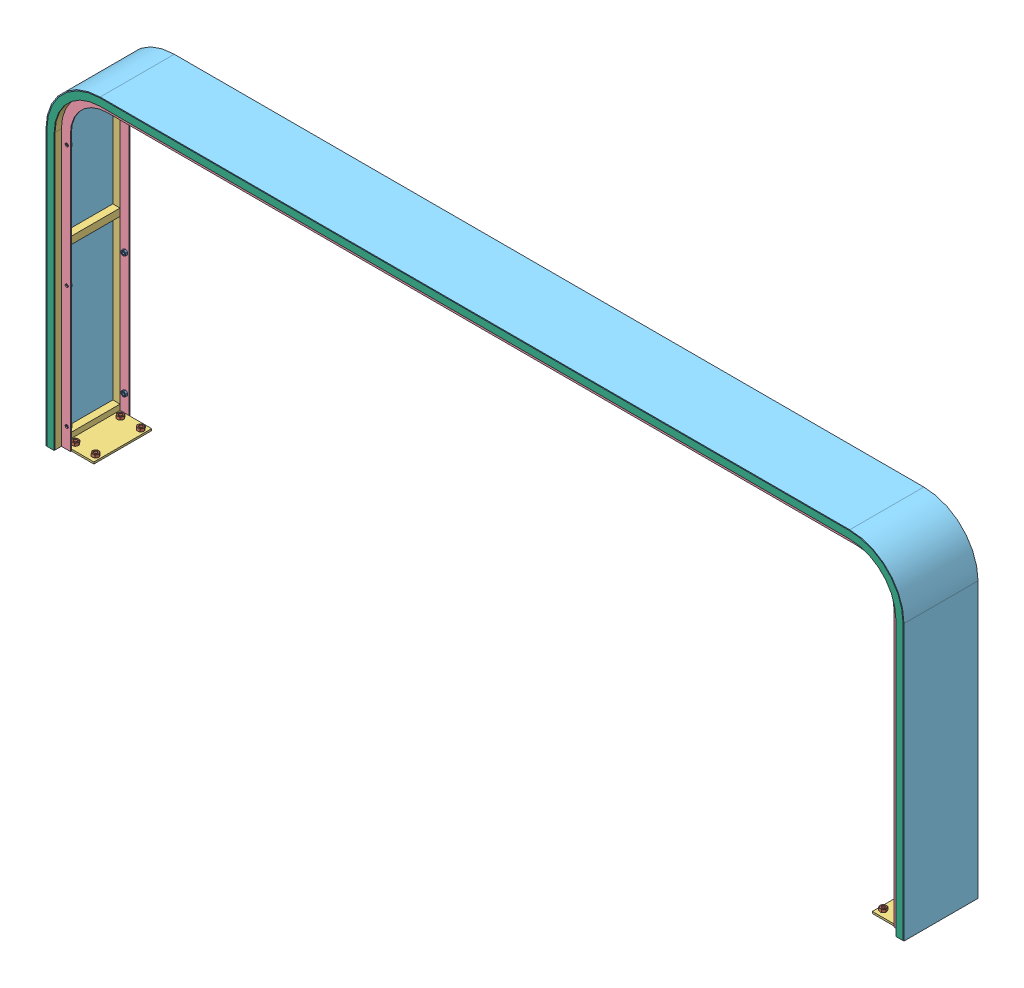
SolidWorks assembly wallFrame1, configuration Default. Lengths in mm.
Overall size (1900 729 164).
36 component instances, 6 part files, 33 mates.
Components (placement in the parent):
- GB_FASTENER_NUT_SNAB1 M6-C-12: GB_FASTENER_NUT_SNAB1 M6-C [GB_FASTENER_NUT_SNAB1 M6-C] at (-920 15 64.0012) x (0.923728 0.383049 0) z (0 0 1) size (11.55 10 5.2)
- GB_FASTENER_NUT_SNAB1 M8-C-5: GB_FASTENER_NUT_SNAB1 M8-C [GB_FASTENER_NUT_SNAB1 M8-C] at (917 -25.0014 -50) x (-0.991729 0 -0.128348) z (0 -1 0) size (15.01 13 6.8)
- table-wallFrame-bone-1: table-wallFrame-bone [Default] at origin size (1896 727 160)
- table-wallFrame-Ufix-1: table-wallFrame-Ufix [Default] at origin size (1864 711 2)
- table-wallFrame-sideshell-1: table-wallFrame-sideshell [Default] at origin size (1900 729 164)
- table-wallFrame-Ushell-1: table-wallFrame-Ushell [Default] at (0 0 -162) size (1896 727 2)
- GB_FASTENER_NUT_SNAB1 M6-C-1: GB_FASTENER_NUT_SNAB1 M6-C [GB_FASTENER_NUT_SNAB1 M6-C] at (-920 15 -58.8) x (0.923728 0.383049 0) z (0 0 1) size (11.55 10 5.2)
- table-wallFrame-Ufix-2: table-wallFrame-Ufix [Default] at (0 0 130) size (1864 711 2)
- table-wallFrame-Ushell-2: table-wallFrame-Ushell [Default] at origin size (1896 727 2)
- GB_FASTENER_NUT_SNAB1 M6-C-23: GB_FASTENER_NUT_SNAB1 M6-C [GB_FASTENER_NUT_SNAB1 M6-C] at (-920 285 -58.8) x (0.923728 0.383049 0) z (0 0 1) size (11.55 10 5.2)
- GB_FASTENER_NUT_SNAB1 M6-C-24: GB_FASTENER_NUT_SNAB1 M6-C [GB_FASTENER_NUT_SNAB1 M6-C] at (-920 555 -58.8) x (0.923728 0.383049 0) z (0 0 1) size (11.55 10 5.2)
- GB_FASTENER_NUT_SNAB1 M6-C-25: GB_FASTENER_NUT_SNAB1 M6-C [GB_FASTENER_NUT_SNAB1 M6-C] at (-800 670 -58.8) x (0.923728 0.383049 0) z (0 0 1) size (11.55 10 5.2)
- GB_FASTENER_NUT_SNAB1 M6-C-26: GB_FASTENER_NUT_SNAB1 M6-C [GB_FASTENER_NUT_SNAB1 M6-C] at (-400 670 -58.8) x (0.923728 0.383049 0) z (0 0 1) size (11.55 10 5.2)
- GB_FASTENER_NUT_SNAB1 M6-C-27: GB_FASTENER_NUT_SNAB1 M6-C [GB_FASTENER_NUT_SNAB1 M6-C] at (0 670 -58.8) x (0.923728 0.383049 0) z (0 0 1) size (11.55 10 5.2)
- GB_FASTENER_NUT_SNAB1 M6-C-28: GB_FASTENER_NUT_SNAB1 M6-C [GB_FASTENER_NUT_SNAB1 M6-C] at (400 670 -58.8) x (0.923728 0.383049 0) z (0 0 1) size (11.55 10 5.2)
- GB_FASTENER_NUT_SNAB1 M6-C-29: GB_FASTENER_NUT_SNAB1 M6-C [GB_FASTENER_NUT_SNAB1 M6-C] at (800 670 -58.8) x (0.923728 0.383049 0) z (0 0 1) size (11.55 10 5.2)
- GB_FASTENER_NUT_SNAB1 M6-C-30: GB_FASTENER_NUT_SNAB1 M6-C [GB_FASTENER_NUT_SNAB1 M6-C] at (920 555 -58.8) x (0.923728 0.383049 0) z (0 0 1) size (11.55 10 5.2)
- GB_FASTENER_NUT_SNAB1 M6-C-31: GB_FASTENER_NUT_SNAB1 M6-C [GB_FASTENER_NUT_SNAB1 M6-C] at (920 285 -58.8) x (0.923728 0.383049 0) z (0 0 1) size (11.55 10 5.2)
- GB_FASTENER_NUT_SNAB1 M6-C-32: GB_FASTENER_NUT_SNAB1 M6-C [GB_FASTENER_NUT_SNAB1 M6-C] at (920 15 -58.8) x (0.923728 0.383049 0) z (0 0 1) size (11.55 10 5.2)
- GB_FASTENER_NUT_SNAB1 M8-C-4: GB_FASTENER_NUT_SNAB1 M8-C [GB_FASTENER_NUT_SNAB1 M8-C] at (-917 -18.2 -50) x (0.991729 0 -0.128348) z (0 1 0) size (15.01 13 6.8)
- GB_FASTENER_NUT_SNAB1 M6-C-33: GB_FASTENER_NUT_SNAB1 M6-C [GB_FASTENER_NUT_SNAB1 M6-C] at (-920 285 64.0012) x (0.923728 0.383049 0) z (0 0 1) size (11.55 10 5.2)
- GB_FASTENER_NUT_SNAB1 M6-C-34: GB_FASTENER_NUT_SNAB1 M6-C [GB_FASTENER_NUT_SNAB1 M6-C] at (-920 555 64.0012) x (0.923728 0.383049 0) z (0 0 1) size (11.55 10 5.2)
- GB_FASTENER_NUT_SNAB1 M6-C-35: GB_FASTENER_NUT_SNAB1 M6-C [GB_FASTENER_NUT_SNAB1 M6-C] at (-800 670 64.0012) x (0.923728 0.383049 0) z (0 0 1) size (11.55 10 5.2)
- GB_FASTENER_NUT_SNAB1 M6-C-36: GB_FASTENER_NUT_SNAB1 M6-C [GB_FASTENER_NUT_SNAB1 M6-C] at (-400 670 64.0012) x (0.923728 0.383049 0) z (0 0 1) size (11.55 10 5.2)
- GB_FASTENER_NUT_SNAB1 M6-C-37: GB_FASTENER_NUT_SNAB1 M6-C [GB_FASTENER_NUT_SNAB1 M6-C] at (0 670 64.0012) x (0.923728 0.383049 0) z (0 0 1) size (11.55 10 5.2)
- GB_FASTENER_NUT_SNAB1 M6-C-38: GB_FASTENER_NUT_SNAB1 M6-C [GB_FASTENER_NUT_SNAB1 M6-C] at (400 670 64.0012) x (0.923728 0.383049 0) z (0 0 1) size (11.55 10 5.2)
- GB_FASTENER_NUT_SNAB1 M6-C-39: GB_FASTENER_NUT_SNAB1 M6-C [GB_FASTENER_NUT_SNAB1 M6-C] at (800 670 64.0012) x (0.923728 0.383049 0) z (0 0 1) size (11.55 10 5.2)
- GB_FASTENER_NUT_SNAB1 M6-C-40: GB_FASTENER_NUT_SNAB1 M6-C [GB_FASTENER_NUT_SNAB1 M6-C] at (920 555 64.0012) x (0.923728 0.383049 0) z (0 0 1) size (11.55 10 5.2)
- GB_FASTENER_NUT_SNAB1 M6-C-41: GB_FASTENER_NUT_SNAB1 M6-C [GB_FASTENER_NUT_SNAB1 M6-C] at (920 15 64.0012) x (0.923728 0.383049 0) z (0 0 1) size (11.55 10 5.2)
- GB_FASTENER_NUT_SNAB1 M6-C-42: GB_FASTENER_NUT_SNAB1 M6-C [GB_FASTENER_NUT_SNAB1 M6-C] at (920 285 64.0012) x (0.923728 0.383049 0) z (0 0 1) size (11.55 10 5.2)
- GB_FASTENER_NUT_SNAB1 M8-C-9: GB_FASTENER_NUT_SNAB1 M8-C [GB_FASTENER_NUT_SNAB1 M8-C] at (-872 -18.2 -50) x (0.991729 0 -0.128348) z (0 1 0) size (15.01 13 6.8)
- GB_FASTENER_NUT_SNAB1 M8-C-10: GB_FASTENER_NUT_SNAB1 M8-C [GB_FASTENER_NUT_SNAB1 M8-C] at (-872 -18.2 50) x (0.991729 0 -0.128348) z (0 1 0) size (15.01 13 6.8)
- GB_FASTENER_NUT_SNAB1 M8-C-11: GB_FASTENER_NUT_SNAB1 M8-C [GB_FASTENER_NUT_SNAB1 M8-C] at (-917 -18.2 50) x (0.991729 0 -0.128348) z (0 1 0) size (15.01 13 6.8)
- GB_FASTENER_NUT_SNAB1 M8-C-12: GB_FASTENER_NUT_SNAB1 M8-C [GB_FASTENER_NUT_SNAB1 M8-C] at (872 -25.0014 -50) x (-0.991729 0 -0.128348) z (0 -1 0) size (15.01 13 6.8)
- GB_FASTENER_NUT_SNAB1 M8-C-13: GB_FASTENER_NUT_SNAB1 M8-C [GB_FASTENER_NUT_SNAB1 M8-C] at (917 -25.0014 50) x (-0.991729 0 -0.128348) z (0 -1 0) size (15.01 13 6.8)
- GB_FASTENER_NUT_SNAB1 M8-C-14: GB_FASTENER_NUT_SNAB1 M8-C [GB_FASTENER_NUT_SNAB1 M8-C] at (872 -25.0014 50) x (-0.991729 0 -0.128348) z (0 -1 0) size (15.01 13 6.8)
Mates (geometry in assembly coordinates):
- 重合1: coincident anti-aligned: plane of table-wallFrame-bone-1 through (830 580 -80) normal (0 0 -1); plane of table-wallFrame-Ushell-1 through (830 580 -80) normal (0 0 1)
- 重合2: coincident aligned: plane of table-wallFrame-bone-1 through (-932 -29 -64) normal (0 -1 0); plane of table-wallFrame-Ushell-1 through (-948 -29 -82) normal (0 -1 0)
- 重合3: coincident aligned: plane of table-wallFrame-bone-1 through (-932 -29 -64) normal (1 0 0); plane of table-wallFrame-Ushell-1 through (-932 -29 -82) normal (1 0 0)
- 同心232: concentric anti-aligned: cylinder of table-wallFrame-Ufix-1 through (-920 15 -78) axis (0 0 -1) radius 3.5; cylinder of GB_FASTENER_NUT_SNAB1 M6-C-1 through (-920 15 -64) axis (0 0 1) radius 2.4585
- 重合4: coincident anti-aligned: plane of table-wallFrame-Ufix-1 through (830 580 -64) normal (0 0 1); plane of GB_FASTENER_NUT_SNAB1 M6-C-1 through (-916.1695 5.7627 -64) normal (0 0 -1)
- 重合5: coincident anti-aligned: plane of table-wallFrame-Ufix-1 through (830 580 -64) normal (0 0 1); plane of GB_FASTENER_NUT_SNAB1 M6-C-23 through (-916.1695 275.7627 -64) normal (0 0 -1)
- 同心233: concentric anti-aligned: cylinder of table-wallFrame-Ufix-1 through (-920 285 -78) axis (0 0 -1) radius 3.5; cylinder of GB_FASTENER_NUT_SNAB1 M6-C-23 through (-920 285 -64) axis (0 0 1) radius 2.4585
- 同心234: concentric anti-aligned: cylinder of table-wallFrame-Ufix-1 through (-920 555 -78) axis (0 0 -1) radius 3.5; cylinder of GB_FASTENER_NUT_SNAB1 M6-C-24 through (-920 555 -64) axis (0 0 1) radius 2.4585
- 重合6: coincident anti-aligned: plane of table-wallFrame-Ufix-1 through (830 580 -64) normal (0 0 1); plane of GB_FASTENER_NUT_SNAB1 M6-C-24 through (-916.1695 545.7627 -64) normal (0 0 -1)
- 同心235: concentric anti-aligned: cylinder of table-wallFrame-Ufix-1 through (-800 670 -78) axis (0 0 -1) radius 3.5; cylinder of GB_FASTENER_NUT_SNAB1 M6-C-25 through (-800 670 -64) axis (0 0 1) radius 2.4585
- 重合7: coincident anti-aligned: plane of table-wallFrame-Ufix-1 through (830 580 -64) normal (0 0 1); plane of GB_FASTENER_NUT_SNAB1 M6-C-25 through (-796.1695 660.7627 -64) normal (0 0 -1)
- 同心236: concentric anti-aligned: cylinder of table-wallFrame-Ufix-1 through (-400 670 -78) axis (0 0 -1) radius 3.5; cylinder of GB_FASTENER_NUT_SNAB1 M6-C-26 through (-400 670 -64) axis (0 0 1) radius 2.4585
- 重合8: coincident anti-aligned: plane of table-wallFrame-Ufix-1 through (830 580 -64) normal (0 0 1); plane of GB_FASTENER_NUT_SNAB1 M6-C-26 through (-396.1695 660.7627 -64) normal (0 0 -1)
- 同心237: concentric anti-aligned: cylinder of table-wallFrame-Ufix-1 through (0 670 -78) axis (0 0 -1) radius 3.5; cylinder of GB_FASTENER_NUT_SNAB1 M6-C-27 through (0 670 -64) axis (0 0 1) radius 2.4585
- 重合9: coincident anti-aligned: plane of table-wallFrame-Ufix-1 through (830 580 -64) normal (0 0 1); plane of GB_FASTENER_NUT_SNAB1 M6-C-27 through (3.8305 660.7627 -64) normal (0 0 -1)
- 同心238: concentric anti-aligned: cylinder of table-wallFrame-Ufix-1 through (400 670 -78) axis (0 0 -1) radius 3.5; cylinder of GB_FASTENER_NUT_SNAB1 M6-C-28 through (400 670 -64) axis (0 0 1) radius 2.4585
- 重合10: coincident anti-aligned: plane of table-wallFrame-Ufix-1 through (830 580 -64) normal (0 0 1); plane of GB_FASTENER_NUT_SNAB1 M6-C-28 through (403.8305 660.7627 -64) normal (0 0 -1)
- 同心239: concentric anti-aligned: cylinder of table-wallFrame-Ufix-1 through (800 670 -78) axis (0 0 -1) radius 3.5; cylinder of GB_FASTENER_NUT_SNAB1 M6-C-29 through (800 670 -64) axis (0 0 1) radius 2.4585
- 重合11: coincident anti-aligned: plane of table-wallFrame-Ufix-1 through (830 580 -64) normal (0 0 1); plane of GB_FASTENER_NUT_SNAB1 M6-C-29 through (803.8305 660.7627 -64) normal (0 0 -1)
- 同心240: concentric anti-aligned: cylinder of table-wallFrame-Ufix-1 through (920 555 -78) axis (0 0 -1) radius 3.5; cylinder of GB_FASTENER_NUT_SNAB1 M6-C-30 through (920 555 -64) axis (0 0 1) radius 2.4585
- 重合12: coincident anti-aligned: plane of table-wallFrame-Ufix-1 through (830 580 -64) normal (0 0 1); plane of GB_FASTENER_NUT_SNAB1 M6-C-30 through (923.8305 545.7627 -64) normal (0 0 -1)
- 同心241: concentric anti-aligned: cylinder of table-wallFrame-Ufix-1 through (920 285 -78) axis (0 0 -1) radius 3.5; cylinder of GB_FASTENER_NUT_SNAB1 M6-C-31 through (920 285 -64) axis (0 0 1) radius 2.4585
- 重合13: coincident anti-aligned: plane of table-wallFrame-Ufix-1 through (830 580 -64) normal (0 0 1); plane of GB_FASTENER_NUT_SNAB1 M6-C-31 through (923.8305 275.7627 -64) normal (0 0 -1)
- 同心242: concentric anti-aligned: cylinder of table-wallFrame-Ufix-1 through (920 15 -78) axis (0 0 -1) radius 3.5; cylinder of GB_FASTENER_NUT_SNAB1 M6-C-32 through (920 15 -64) axis (0 0 1) radius 2.4585
- 重合14: coincident anti-aligned: plane of table-wallFrame-Ufix-1 through (830 580 -64) normal (0 0 1); plane of GB_FASTENER_NUT_SNAB1 M6-C-32 through (923.8305 5.7627 -64) normal (0 0 -1)
- 同心243: concentric aligned: cylinder of table-wallFrame-bone-1 through (-917 -25 -50) axis (0 1 0) radius 4.5; cylinder of GB_FASTENER_NUT_SNAB1 M8-C-4 through (-917 -25 -50) axis (0 1 0) radius 3.3235
- 重合15: coincident anti-aligned: plane of table-wallFrame-bone-1 through (-862 -25 64) normal (0 1 0); plane of GB_FASTENER_NUT_SNAB1 M8-C-4 through (-909.5565 -25 -50.9633) normal (0 -1 0)
- 重合16: coincident anti-aligned: plane of table-wallFrame-bone-1 through (-862 -25 64) normal (0 1 0); plane of GB_FASTENER_NUT_SNAB1 M8-C-9 through (-864.5565 -25 -50.9633) normal (0 -1 0)
- 同心244: concentric aligned: cylinder of table-wallFrame-bone-1 through (-872 -25 -50) axis (0 1 0) radius 4.5; cylinder of GB_FASTENER_NUT_SNAB1 M8-C-9 through (-872 -25 -50) axis (0 1 0) radius 3.3235
- 同心245: concentric aligned: cylinder of table-wallFrame-bone-1 through (-872 -25 50) axis (0 1 0) radius 4.5; cylinder of GB_FASTENER_NUT_SNAB1 M8-C-10 through (-872 -25 50) axis (0 1 0) radius 3.3235
- 重合17: coincident anti-aligned: plane of table-wallFrame-bone-1 through (-862 -25 64) normal (0 1 0); plane of GB_FASTENER_NUT_SNAB1 M8-C-10 through (-864.5565 -25 49.0367) normal (0 -1 0)
- 同心246: concentric aligned: cylinder of table-wallFrame-bone-1 through (-917 -25 50) axis (0 1 0) radius 4.5; cylinder of GB_FASTENER_NUT_SNAB1 M8-C-11 through (-917 -25 50) axis (0 1 0) radius 3.3235
- 重合18: coincident anti-aligned: plane of table-wallFrame-bone-1 through (-862 -25 64) normal (0 1 0); plane of GB_FASTENER_NUT_SNAB1 M8-C-11 through (-909.5565 -25 49.0367) normal (0 -1 0)
